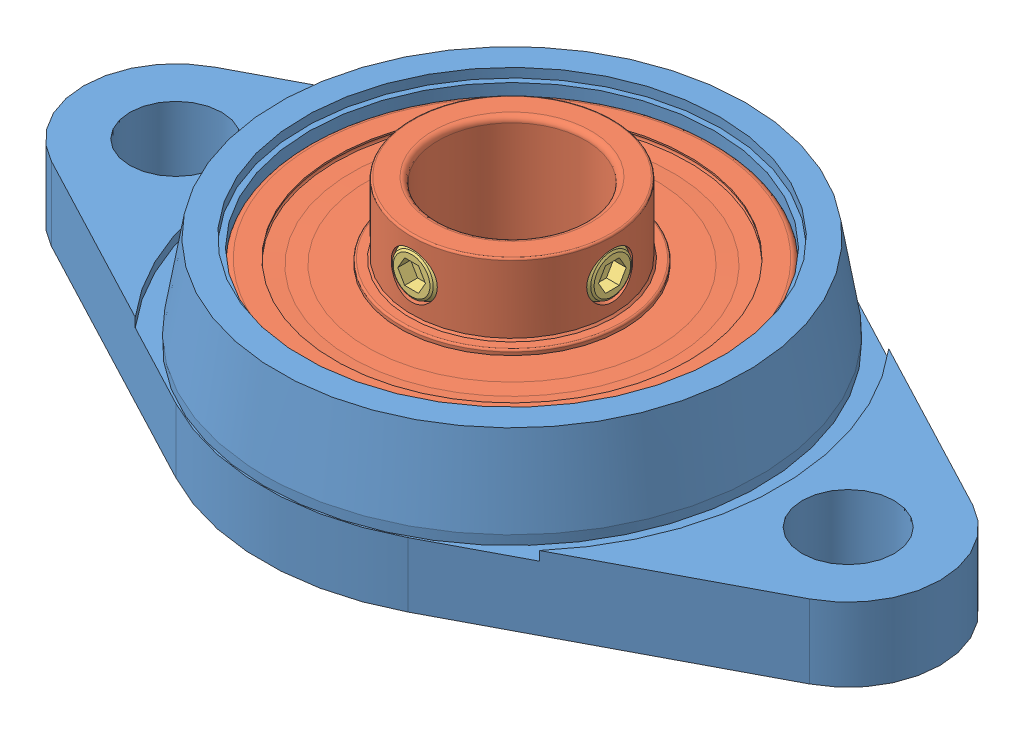
SolidWorks assembly KFL08, configuration Varsayılan. Lengths in mm.
Overall size (46.5 11.35 27).
4 component instances, 3 part files, 9 mates.
Components (placement in the parent):
- Copia de FLANGE-1: Copia de FLANGE [Default] at origin size (46.5 8.5 27)
- Copia de BEARING-1: Copia de BEARING [Default] at (0 4 0) x (1 0 0) z (0 -1 0) size (22 22 10.85)
- socket set screw cone point_am-1: socket set screw cone point_am [B18.3.6M - M2.5 x 0.45 x 2 Hex Socket Cone Pt. SS --S] at (0 9.425 5.45) x (0 0 -1) z (1 0 0) size (2 2.5 2.5)
- socket set screw cone point_am-2: socket set screw cone point_am [B18.3.6M - M2.5 x 0.45 x 2 Hex Socket Cone Pt. SS --S] at (5.45 9.425 0) x (-1 0 0) z (0 0 -1) size (2 2.5 2.5)
Mates (geometry in assembly coordinates):
- Concentric1: concentric aligned: cylinder of Copia de FLANGE-1 through (0 4 0) axis (0 -1 0) radius 11; cylinder of Copia de BEARING-1 through (0 0.5 0) axis (0 -1 0) radius 11
- Coincident1: coincident aligned: plane of Copia de FLANGE-1 through (0 0.5 0) normal (0 -1 0); plane of Copia de BEARING-1 through (0 0.5 9.6) normal (0 -1 0)
- Coincident3: coincident aligned: plane of Copia de FLANGE-1 through (0 0 0) normal (1 0 0); plane of Copia de BEARING-1 through (0 4 0) normal (1 0 0)
- Concentric2: concentric aligned: cylinder of Copia de BEARING-1 through (0 9.425 5.45) axis (0 0 1) radius 1.25; cylinder of socket set screw cone point_am-1 through (0 9.425 18.15) axis (0 0 1) radius 1.25
- Tangent1: tangent aligned: cylinder of Copia de BEARING-1 through (0 0.5 0) axis (0 -1 0) radius 5.45; plane of socket set screw cone point_am-1 through (0 9.425 5.45) normal (0 0 1)
- Concentric3: concentric aligned: cylinder of Copia de BEARING-1 through (5.45 9.425 0) axis (1 0 0) radius 1.25; cylinder of socket set screw cone point_am-2 through (18.15 9.425 0) axis (1 0 0) radius 1.25
- Tangent3: tangent aligned: cylinder of Copia de BEARING-1 through (0 0.5 0) axis (0 -1 0) radius 5.45; plane of socket set screw cone point_am-2 through (5.45 9.425 0) normal (1 0 0)
- Parallel1: parallel aligned: plane of socket set screw cone point_am-1 through (0 9.425 5.45) normal (0 1 0); plane of assembly through (0 0 0) normal (0 1 0)
- Parallel2: parallel aligned: plane of socket set screw cone point_am-2 through (5.45 9.425 0) normal (0 1 0); plane of assembly through (0 0 0) normal (0 1 0)
